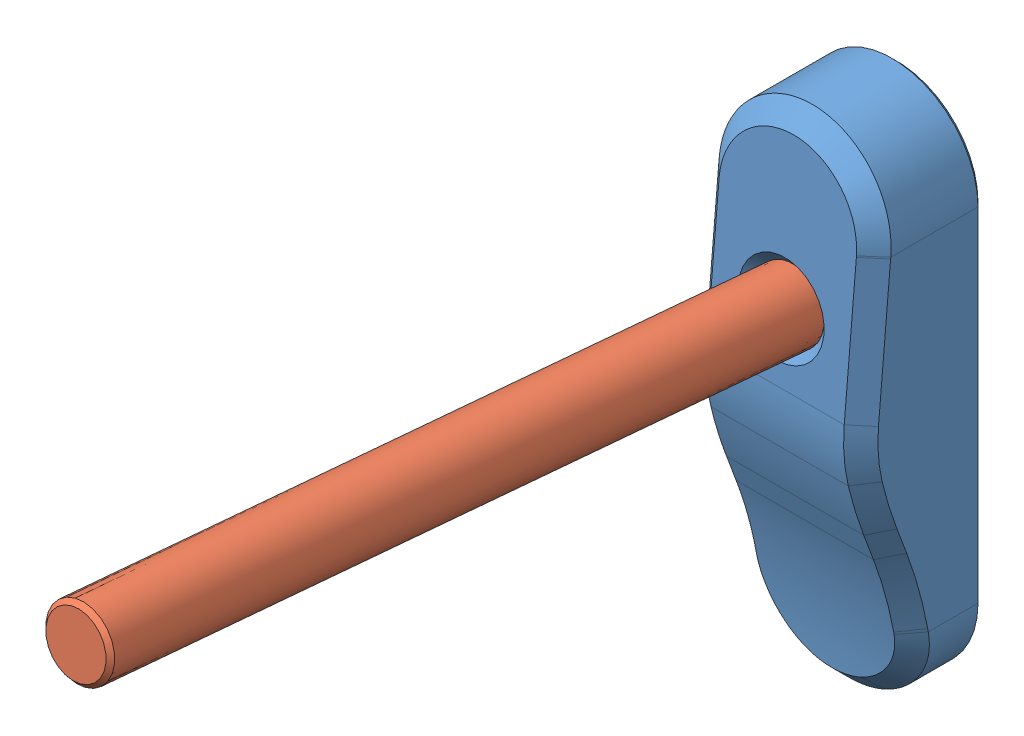
SolidWorks assembly Spool Carrier ASM, configuration Default. Lengths in mm.
Overall size (20.23 60 96.11).
2 component instances, 2 part files, 2 mates.
Components (placement in the parent):
- Spool Carrier-1: Spool Carrier [Default] at origin size (20.23 60 14.17)
- Spool Bar-1: Spool Bar [Default] at (0 0.5229 5.9772) x (0.851662 -0.522097 0.045678) z (0 0.087156 0.996195) size (8 8 90)
Mates (geometry in assembly coordinates):
- Concentric1: concentric: cylinder of Spool Carrier-1 through (0 0.5229 5.9772) axis (0 0.087156 0.996195) radius 4; cylinder of Spool Bar-1 through (0 3.8564 44.0784) axis (0 0.087156 0.996195) radius 4
- Coincident1: coincident anti-aligned: plane of Spool Carrier-1 through (0 0.5229 5.9772) normal (0 0.087156 0.996195); plane of Spool Bar-1 through (0 0.5229 5.9772) normal (0 -0.087156 -0.996195)
